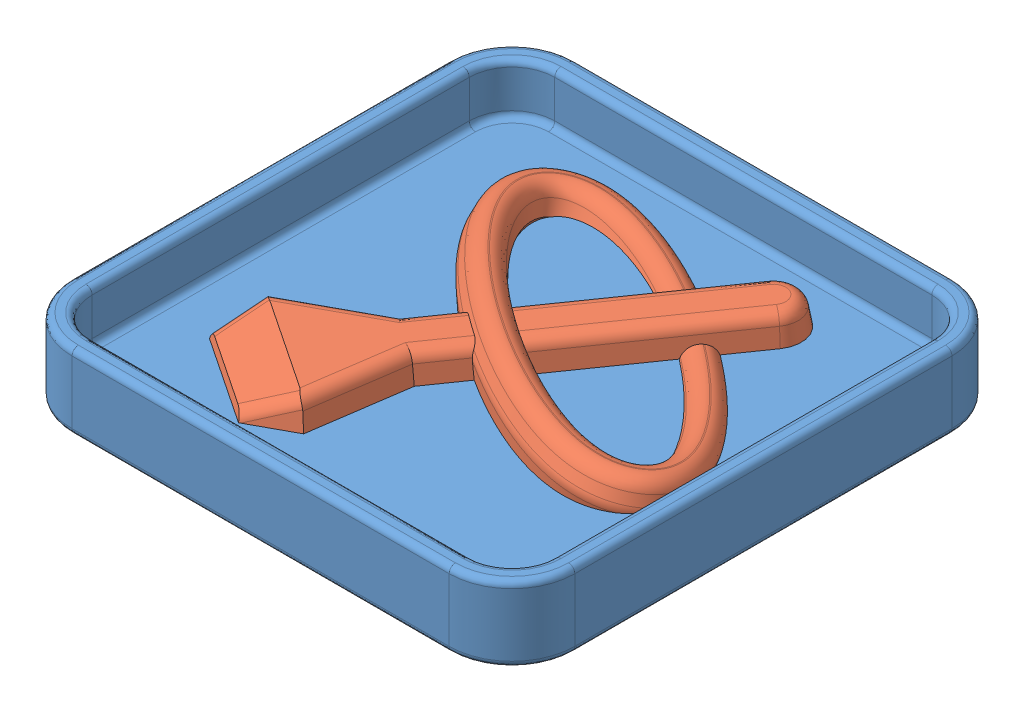
SolidWorks assembly Assem4, configuration Default. Lengths in mm.
Overall size (40 7.11 40).
2 component instances, 2 part files, 2 mates.
Components (placement in the parent):
- Tile-1: Tile [Default] at (9.8782 17.4002 33.6917) size (40 6 40)
- SpaceStation-1: SpaceStation [Default] at (10.1117 19.4002 33.2917) size (35 7.09 35)
Mates (geometry in assembly coordinates):
- Coincident1: coincident anti-aligned: plane of Tile-1 through (-5.1218 19.4002 48.6917) normal (0 1 0); plane of SpaceStation-1 through (17.231 19.4002 20.2502) normal (0 -1 0)
- Coincident2: coincident anti-aligned: line of Tile-1 through (24.8782 19.4002 15.7917) axis (-1 0 0); line of SpaceStation-1 through (-7.3883 19.4002 15.7917) axis (1 0 0)
